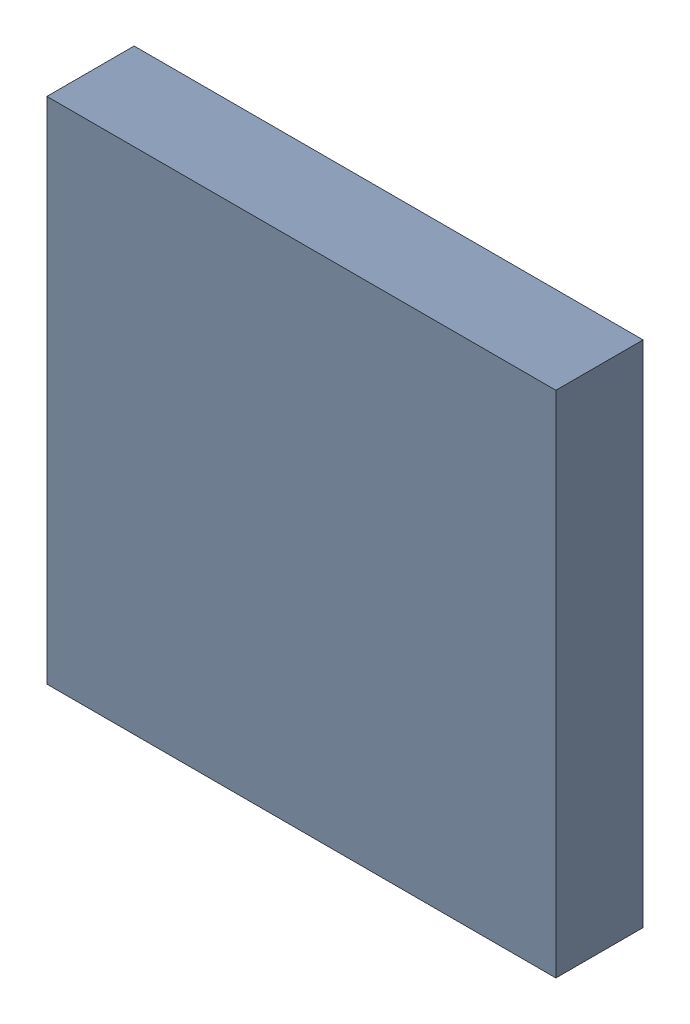
SolidWorks assembly U4-2, configuration Default. Lengths in mm.
Overall size (7 7 1.2).
2 component instances, 1 part files, 0 mates.
Components (placement in the parent):
- 959209752-2-1: 959209752-2 [Default] at (110.9632 83.702 0) size (7 7 1.2)
  - Extruded-90-1: Extruded-90 [Default] at origin size (7 7 1.2)
